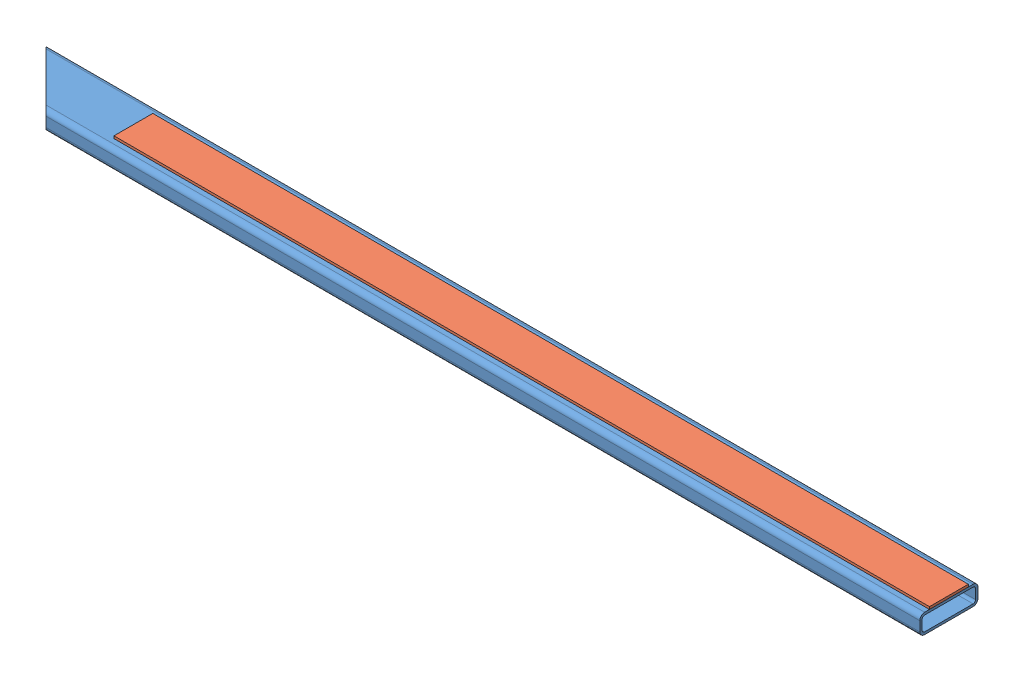
SolidWorks assembly GE-19168, configuration blue. Lengths in mm.
Overall size (1219.2 28.57 76.2).
2 component instances, 2 part files, 3 mates.
Components (placement in the parent):
- GE-19039-1: GE-19039 [blue] at origin size (1219.2 25.4 76.2)
- Hook_2_42-1: Hook_2_42 [Default] at (1219.2 25.4 -63.5) x (1 0 0) z (0 1 0) size (1066.8 50.8 3.17)
Mates (geometry in assembly coordinates):
- Coincident2: coincident: plane of GE-19039-1 through (1219.2 0 0) normal (1 0 0); plane of Hook_2_42-1 through (1219.2 28.575 -63.5) normal (1 0 0)
- Width1: width: plane of Hook_2_42-1 through (1219.2 28.575 -12.7) normal (0 0 1); plane of Hook_2_42-1 through (1219.2 28.575 -63.5) normal (0 0 -1); plane of GE-19039-1 through (1219.2 0 0) normal (0 0 1); plane of GE-19039-1 through (1219.2 0 -76.2) normal (0 0 -1)
- Coincident3: coincident: plane of GE-19039-1 through (1219.2 25.4 0) normal (0 1 0); plane of Hook_2_42-1 through (1219.2 25.4 -63.5) normal (0 -1 0)
